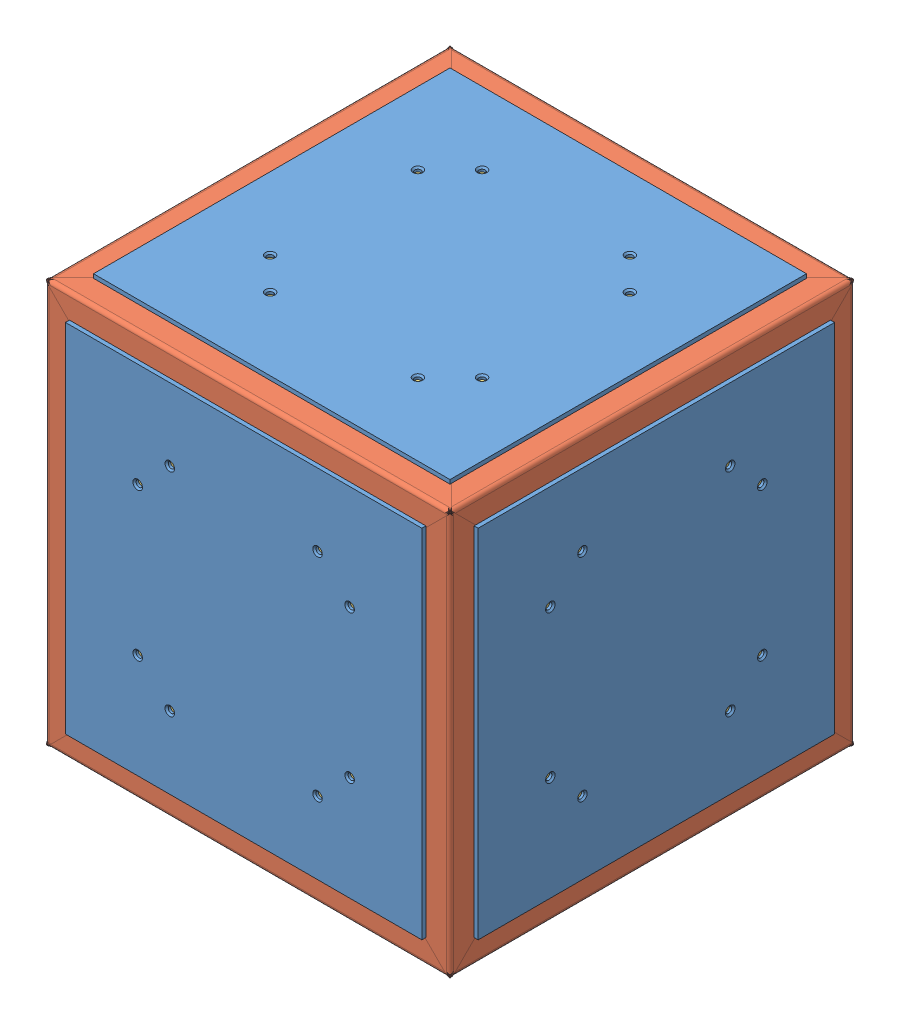
SolidWorks assembly master_cube, configuration cube01. Lengths in mm.
Overall size (163.19 163.19 163.19).
43 component instances, 5 part files, 15 mates.
Components (placement in the parent):
- panel^master_cube-2: panel^master_cube [cube01] x (-1 0 0) z (0 0 1) size (140.97 1.59 140.97) (virtual)
- diffuser^master_cube-2: diffuser^master_cube [cube01] at (-79.4046 80.01 0) x (0 -1 0) z (0 0 1) size (26.01 26.01 160.03) (virtual)
- bracket^master_cube-4: bracket^master_cube [Default] at (-54.61 54.61 0) size (50.8 50.8 102.11) (virtual)
- light_strip^master_cube-2: light_strip^master_cube [Default] at (-61.1594 78.2606 0) x (0 0 -1) z (-1 0 0) size (88.9 1.2 10) (virtual)
- bracket^master_cube-19: bracket^master_cube [Default] at (0 54.61 -54.61) x (0 0 1) z (-1 0 0) size (50.8 50.8 102.11) (virtual)
- bracket^master_cube-27: bracket^master_cube [Default] at (0 54.61 54.61) x (0 0 -1) z (1 0 0) size (50.8 50.8 102.11) (virtual)
- diffuser^master_cube-18: diffuser^master_cube [cube01] at (0 80.01 -79.4046) x (0 -1 0) z (-1 0 0) size (26.01 26.01 160.03) (virtual)
- diffuser^master_cube-19: diffuser^master_cube [cube01] at (0 80.01 79.4046) x (0 -1 0) z (1 0 0) size (26.01 26.01 160.03) (virtual)
- bracket^master_cube-24: bracket^master_cube [Default] at (-54.61 0 -54.61) x (0 0 1) z (0 -1 0) size (50.8 50.8 102.11) (virtual)
- bracket^master_cube-25: bracket^master_cube [Default] at (0 -54.61 -54.61) x (0 0 1) z (1 0 0) size (50.8 50.8 102.11) (virtual)
- bracket^master_cube-26: bracket^master_cube [Default] at (54.61 0 -54.61) x (0 0 1) z (0 1 0) size (50.8 50.8 102.11) (virtual)
- bracket^master_cube-28: bracket^master_cube [Default] at (-54.61 0 54.61) x (0 0 -1) z (0 1 0) size (50.8 50.8 102.11) (virtual)
- bracket^master_cube-29: bracket^master_cube [Default] at (0 -54.61 54.61) x (0 0 -1) z (-1 0 0) size (50.8 50.8 102.11) (virtual)
- bracket^master_cube-30: bracket^master_cube [Default] at (54.61 0 54.61) x (0 0 -1) z (0 -1 0) size (50.8 50.8 102.11) (virtual)
- diffuser^master_cube-23: diffuser^master_cube [cube01] at (-80.01 0 -79.4046) x (1 0 0) z (0 -1 0) size (26.01 26.01 160.03) (virtual)
- diffuser^master_cube-24: diffuser^master_cube [cube01] at (0 -80.01 -79.4046) x (0 1 0) z (1 0 0) size (26.01 26.01 160.03) (virtual)
- diffuser^master_cube-25: diffuser^master_cube [cube01] at (80.01 0 -79.4046) x (-1 0 0) z (0 1 0) size (26.01 26.01 160.03) (virtual)
- diffuser^master_cube-26: diffuser^master_cube [cube01] at (-80.01 0 79.4046) x (1 0 0) z (0 1 0) size (26.01 26.01 160.03) (virtual)
- diffuser^master_cube-27: diffuser^master_cube [cube01] at (0 -80.01 79.4046) x (0 1 0) z (-1 0 0) size (26.01 26.01 160.03) (virtual)
- diffuser^master_cube-28: diffuser^master_cube [cube01] at (80.01 0 79.4046) x (-1 0 0) z (0 -1 0) size (26.01 26.01 160.03) (virtual)
- panel^master_cube-11: panel^master_cube [cube01] x (-1 0 0) z (0 -1 0) size (140.97 1.59 140.97) (virtual)
- panel^master_cube-12: panel^master_cube [cube01] x (-1 0 0) z (0 1 0) size (140.97 1.59 140.97) (virtual)
- light_shelf^master_cube-1: light_shelf^master_cube [Default] at (-55.4228 72.1106 0) x (0 0 1) z (0 -1 0) size (69.09 10.16 13.51) (virtual)
- light_shelf^master_cube-2: light_shelf^master_cube [Default] at (0 72.1106 -55.4228) x (-1 0 0) z (0 -1 0) size (69.09 10.16 13.51) (suppressed, hidden, virtual)
- light_shelf^master_cube-3: light_shelf^master_cube [Default] at (0 72.1106 55.4228) x (1 0 0) z (0 -1 0) size (69.09 10.16 13.51) (suppressed, hidden, virtual)
- light_shelf^master_cube-4: light_shelf^master_cube [Default] at (-72.1106 -55.4228 0) x (0 0 1) z (1 0 0) size (69.09 10.16 13.51) (virtual)
- light_shelf^master_cube-5: light_shelf^master_cube [Default] at (55.4228 -72.1106 0) x (0 0 1) z (0 1 0) size (69.09 10.16 13.51) (virtual)
- light_shelf^master_cube-6: light_shelf^master_cube [Default] at (72.1106 55.4228 0) x (0 0 1) z (-1 0 0) size (69.09 10.16 13.51) (virtual)
- light_shelf^master_cube-7: light_shelf^master_cube [Default] at (-72.1106 0 -55.4228) x (0 -1 0) z (1 0 0) size (69.09 10.16 13.51) (virtual)
- light_shelf^master_cube-8: light_shelf^master_cube [Default] at (0 -72.1106 -55.4228) x (1 0 0) z (0 1 0) size (69.09 10.16 13.51) (virtual)
- light_shelf^master_cube-9: light_shelf^master_cube [Default] at (72.1106 0 -55.4228) x (0 1 0) z (-1 0 0) size (69.09 10.16 13.51) (virtual)
- light_shelf^master_cube-10: light_shelf^master_cube [Default] at (-72.1106 0 55.4228) x (0 1 0) z (1 0 0) size (69.09 10.16 13.51) (virtual)
- light_shelf^master_cube-11: light_shelf^master_cube [Default] at (0 -72.1106 55.4228) x (-1 0 0) z (0 1 0) size (69.09 10.16 13.51) (virtual)
- light_shelf^master_cube-12: light_shelf^master_cube [Default] at (72.1106 0 55.4228) x (0 -1 0) z (-1 0 0) size (69.09 10.16 13.51) (virtual)
- diffuser^master_cube-29: diffuser^master_cube [cube01] at (-80.01 -79.4046 0) size (26.01 26.01 160.03) (virtual)
- diffuser^master_cube-30: diffuser^master_cube [cube01] at (79.4046 -80.01 0) x (0 1 0) z (0 0 1) size (26.01 26.01 160.03) (virtual)
- diffuser^master_cube-31: diffuser^master_cube [cube01] at (80.01 79.4046 0) x (-1 0 0) z (0 0 1) size (26.01 26.01 160.03) (virtual)
- bracket^master_cube-34: bracket^master_cube [Default] at (-54.61 -54.61 0) x (0 1 0) z (0 0 1) size (50.8 50.8 102.11) (virtual)
- bracket^master_cube-35: bracket^master_cube [Default] at (54.61 -54.61 0) x (-1 0 0) z (0 0 1) size (50.8 50.8 102.11) (virtual)
- bracket^master_cube-36: bracket^master_cube [Default] at (54.61 54.61 0) x (0 -1 0) z (0 0 1) size (50.8 50.8 102.11) (virtual)
- panel^master_cube-13: panel^master_cube [cube01] x (0 -1 0) z (0 0 1) size (140.97 1.59 140.97) (virtual)
- panel^master_cube-14: panel^master_cube [cube01] at origin size (140.97 1.59 140.97) (virtual)
- panel^master_cube-15: panel^master_cube [cube01] x (0 1 0) z (0 0 1) size (140.97 1.59 140.97) (virtual)
Mates (geometry in assembly coordinates):
- Coincident9: coincident aligned: plane of panel^master_cube-2 through (0 0 0) normal (0 0 1); plane of diffuser^master_cube-2 through (-79.4046 80.01 0) normal (0 0 1)
- Coincident11: coincident anti-aligned: plane of panel^master_cube-2 through (70.485 80.01 -70.485) normal (0 -1 0); plane of diffuser^master_cube-2 through (-159.4146 80.01 0) normal (0 1 0)
- Coincident1: coincident aligned: plane of panel^master_cube-2 through (0 0 0) normal (0 0 1); plane of assembly through (0 0 0) normal (0 0 1)
- Coincident2: coincident anti-aligned: plane of panel^master_cube-2; plane of assembly through (0 0 0) normal (1 0 0)
- Coincident3: coincident anti-aligned: plane of panel^master_cube-2; plane of assembly through (0 0 0) normal (0 1 0)
- Coincident13: coincident anti-aligned: plane of panel^master_cube-2 through (70.485 80.01 -70.485) normal (0 -1 0); plane of bracket^master_cube-4 through (-54.61 80.01 51.054) normal (0 1 0)
- Coincident24: coincident aligned: plane of bracket^master_cube-4 through (-54.61 54.61 0) normal (0 0 1); plane of assembly through (0 0 0) normal (0 0 1)
- Coincident25: coincident aligned: plane of diffuser^master_cube-2 through (-80.01 -0.6054 0) normal (-1 0 0); plane of bracket^master_cube-4 through (-80.01 54.61 51.054) normal (-1 0 0)
- Distance1: distance aligned: plane of bracket^master_cube-4 through (-80.01 54.61 51.054) normal (-1 0 0); plane of panel^master_cube-2 through (-70.485 81.5975 70.485) normal (-1 0 0)
- Coincident30: coincident anti-aligned: plane of light_strip^master_cube-2; plane of assembly through (0 0 0) normal (0 0 1)
- Coincident35: coincident aligned: plane of light_shelf^master_cube-1; plane of assembly through (0 0 0) normal (0 0 1)
- Coincident38: coincident anti-aligned: plane of bracket^master_cube-4 through (-54.61 54.61 51.054) normal (-1 0 0); plane of light_shelf^master_cube-1 through (-54.61 78.4606 34.544) normal (1 0 0)
- Coincident39: coincident anti-aligned: plane of light_strip^master_cube-2 through (-66.1594 78.4606 -44.45) normal (0 1 0); plane of light_shelf^master_cube-1 through (-64.77 78.4606 34.544) normal (0 -1 0)
- Coincident41: coincident anti-aligned: line of light_strip^master_cube-2 through (-56.1594 78.4606 -44.45) axis (0 0 1); line of light_shelf^master_cube-1 through (-56.1594 78.4606 34.544) axis (0 0 -1)
- Coincident46: coincident anti-aligned: plane of diffuser^master_cube-2 through (-159.4146 79.2734 0) normal (0 -1 0); plane of light_shelf^master_cube-1 through (-64.77 79.2734 34.544) normal (0 1 0)
